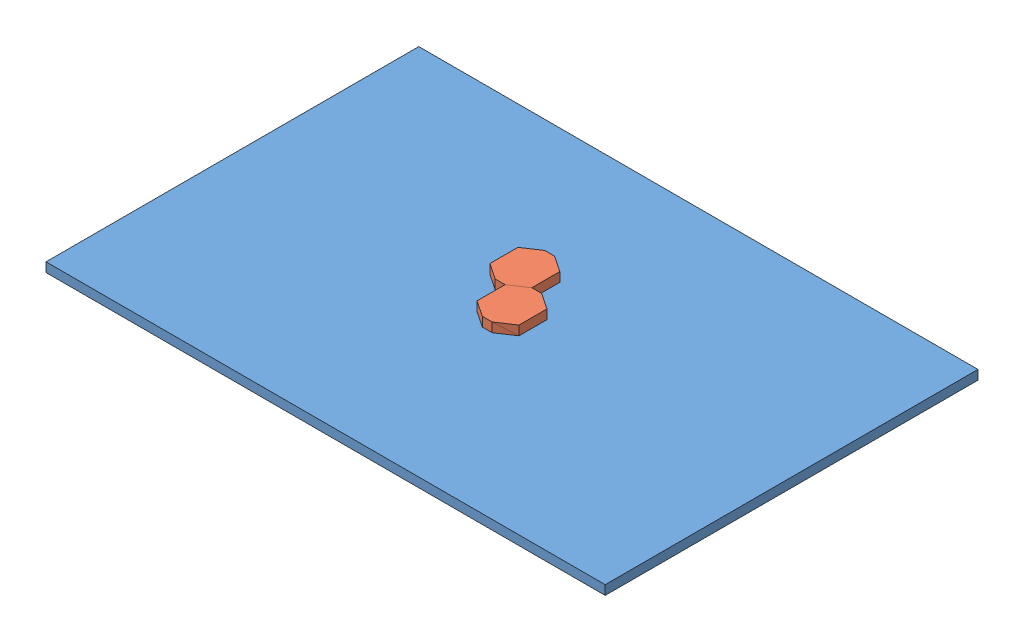
SolidWorks assembly two_node_5625, configuration Default. Lengths in mm.
Overall size (600 20 400).
3 component instances, 2 part files, 7 mates.
Components (placement in the parent):
- ground-1: ground [Default] at origin size (600 10 400)
- node_5625-1: node_5625 [Default] at origin size (45 10 53.08)
- node_5625-2: node_5625 [Default] at (-27.7785 0 -41.5735) size (45 10 53.08)
Mates (geometry in assembly coordinates):
- Coincident1: coincident aligned: plane of ground-1 through (0 0 0) normal (0 0 1)
- Coincident2: coincident aligned: plane of ground-1 through (0 0 0) normal (0 1 0)
- Coincident3: coincident aligned: plane of ground-1 through (0 0 0) normal (1 0 0)
- Coincident4: coincident aligned: plane of node_5625-1 through (0 0 0) normal (0 0 1)
- Coincident5: coincident aligned: plane of node_5625-1 through (0 0 0) normal (0 1 0)
- Coincident6: coincident aligned: plane of node_5625-1 through (0 0 0) normal (1 0 0)
- Coincident7: coincident: point of node_5625-1; unknown of node_5625-2
